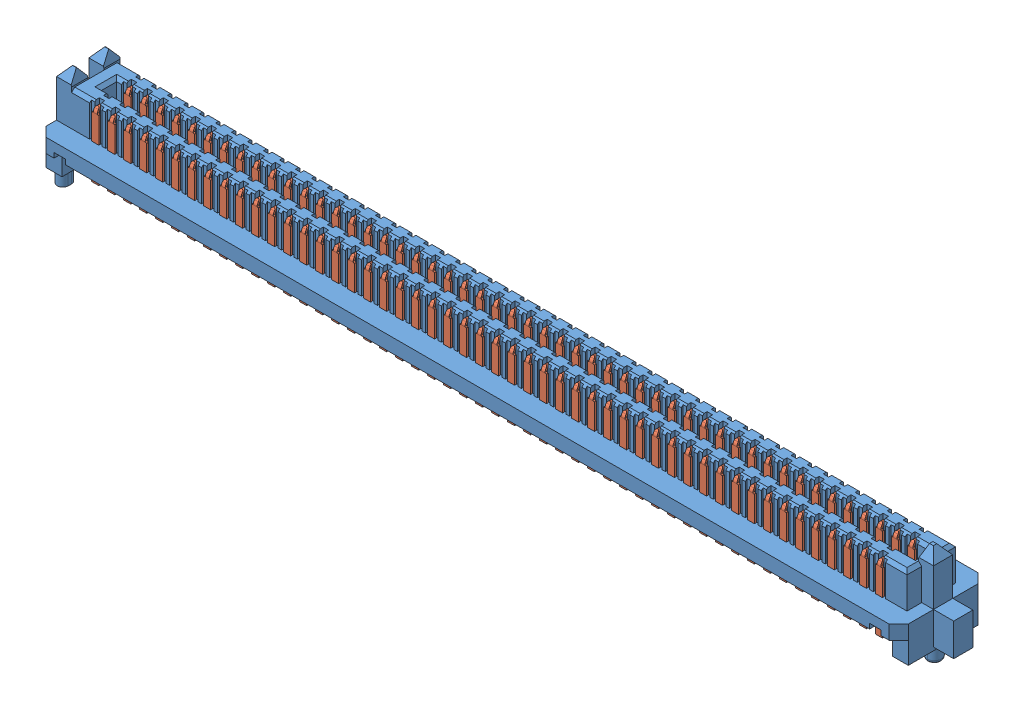
SolidWorks assembly SEAM_50_03_0_L_04_2_A_K_TR, configuration Default. Lengths in mm.
Overall size (70.08 7.87 7.06).
4 component instances, 4 part files, 0 mates.
Components (placement in the parent):
- _SEAM_50_03_0_L_04_1_A_K_TR_body_2-1: _SEAM_50_03_0_L_04_1_A_K_TR_body_2 [Default] at origin size (70.08 7.87 7.06)
- _SEAM_50_03_0_L_04_1_A_K_TR_conn_4-1: _SEAM_50_03_0_L_04_1_A_K_TR_conn_4 [Default] at origin size (67.97 5.25 6.55)
- _SEAM_K_Pad_04_6-1: _SEAM_K_Pad_04_6 [Default] at (0 2.7432 0) size (5.99 0.13 5.99) (hidden)
- _SEAM_Triangle_8-1: _SEAM_Triangle_8 [Default] at (32.2834 1.3462 -1.6764) x (-1 0 0) z (0 0 -1) size (1.02 1.27 0.13)
